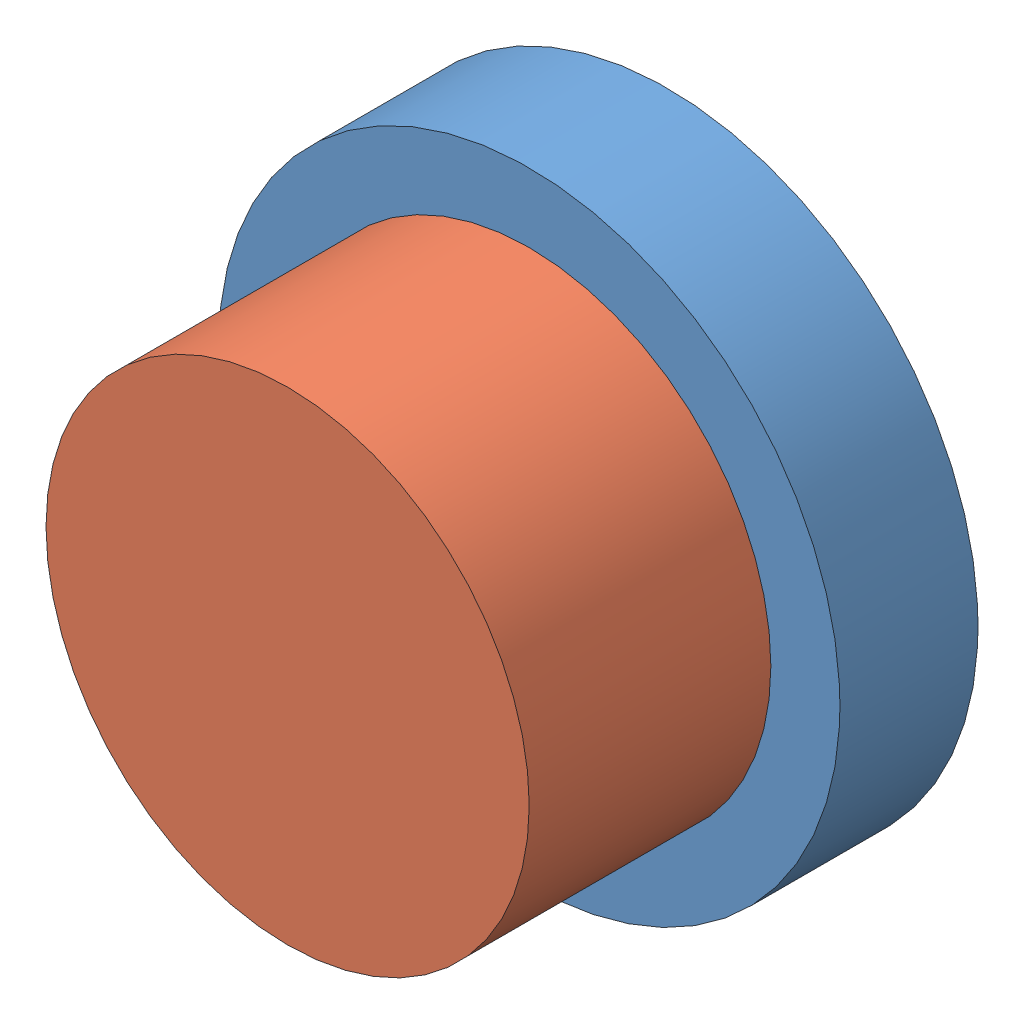
SolidWorks assembly Assem1, configuration Default. Lengths in mm.
Overall size (22.86 22.86 13.97).
2 component instances, 2 part files, 2 mates.
Components (placement in the parent):
- Holder-1: Holder [Default] at (9.7432 11.6607 14.5511) size (22.86 22.86 5.08)
- red-1: red [Default] at (9.7432 11.6607 19.6311) size (17.78 17.78 8.89)
Mates (geometry in assembly coordinates):
- Coincident1: coincident: plane of Holder-1 through (9.7432 11.6607 19.6311) normal (0 0 1); plane of red-1 through (9.7432 11.6607 19.6311) normal (0 0 -1)
- Concentric1: concentric aligned: circle of Holder-1; circle of red-1
